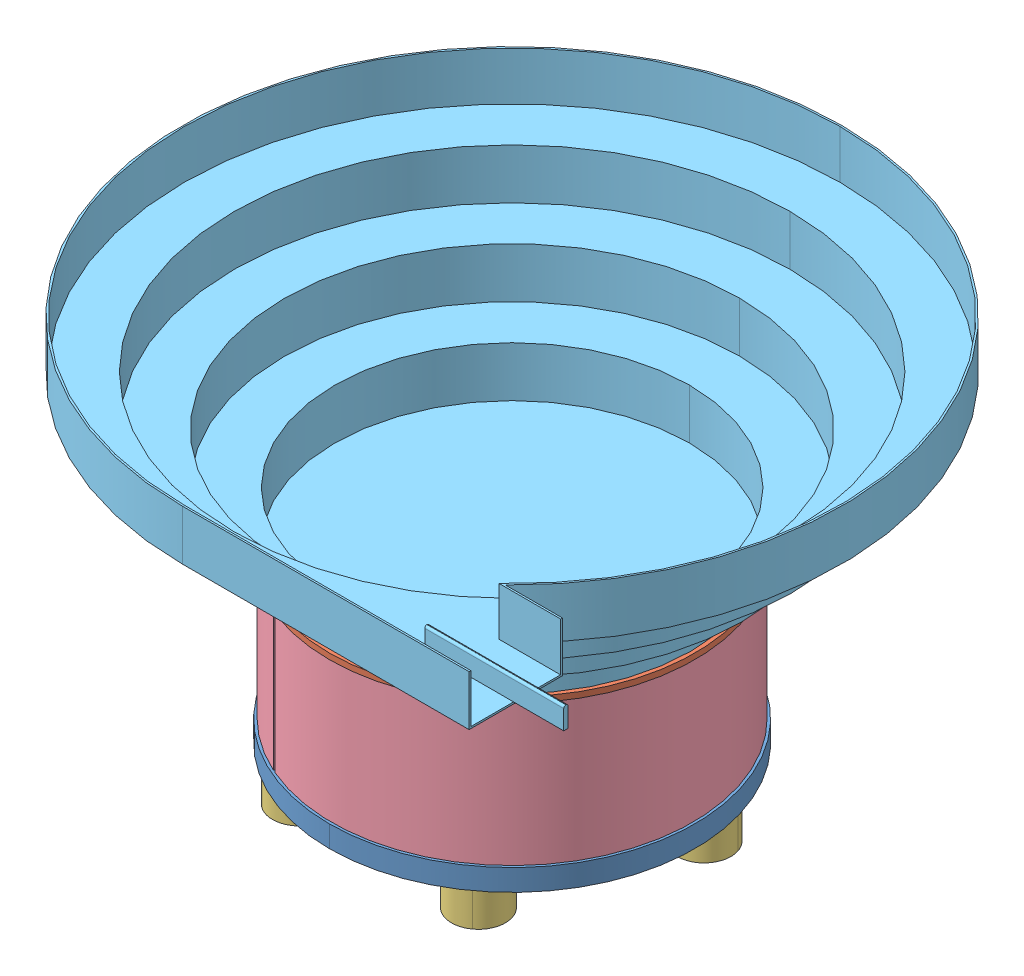
SolidWorks assembly vibratory-bowl-feeder, configuration Default. Lengths in mm.
Overall size (930 566.38 920).
11 component instances, 5 part files, 0 mates.
Components (placement in the parent):
- VibratoryFeeder-1: VibratoryFeeder [Default] at origin size (930 566.38 920)
  - IT-028-01 (DRIVE ASSEMBLY)-1: IT-028-01 (DRIVE ASSEMBLY) [Default] at origin size (705.9 286.38 705.9)
    - IT-028-01-001 (500 DRIVE BASE)-1: IT-028-01-001 (500 DRIVE BASE) [Default] at origin size (510 60 510)
    - IT-028-01-003 (500 DRIVE TOP)-1: IT-028-01-003 (500 DRIVE TOP) [Default] at (0 236.3816 0) x (-0.837169 0 -0.546944) z (-0.546944 0 0.837169) size (510 20 510)
    - M12 AV PADS-1: M12 AV PADS [Default] at (0 -50 -212.5) size (75 70 75)
    - M12 AV PADS-2: M12 AV PADS [Default] at (-202.0995 -50 -65.6661) x (0.309017 0 -0.951057) z (0.951057 0 0.309017) size (75 70 75)
    - M12 AV PADS-3: M12 AV PADS [Default] at (-124.9044 -50 171.9161) x (-0.809017 0 -0.587785) z (0.587785 0 -0.809017) size (75 70 75)
    - M12 AV PADS-4: M12 AV PADS [Default] at (124.9044 -50 171.9161) x (-0.809017 0 0.587785) z (-0.587785 0 -0.809017) size (75 70 75)
    - M12 AV PADS-5: M12 AV PADS [Default] at (202.0995 -50 -65.6661) x (0.309017 0 0.951057) z (-0.951057 0 0.309017) size (75 70 75)
    - IT-028-01-006 (COVER)-1: IT-028-01-006 (COVER) [Default] at (0 30 0) x (0.914466 0 0.404664) z (-0.404664 0 0.914466) size (503.2 198 503.19)
  - 028 BOWL DEMO-1: 028 BOWL DEMO [Default] at (0 236.3816 0) size (930 280 920)
